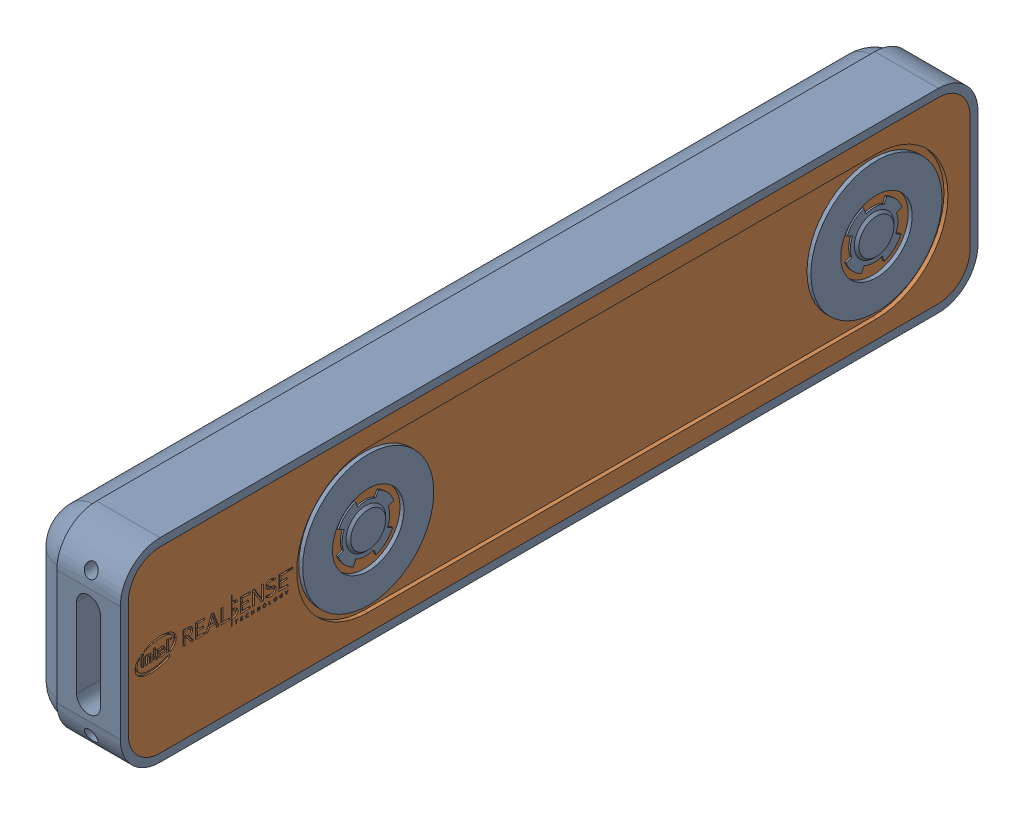
SolidWorks assembly Intel RealSense T265.step, configuration Default. Lengths in mm.
Overall size (12.5 24.5 108).
2 component instances, 2 part files, 0 mates.
Components (placement in the parent):
- body.step-1: body.step [Default] at (-0.0259 -0.3151 0.4547) x (1 0 0) z (0 1 0) size (12.5 108 24.5)
- cover.step-1: cover.step [Default] at (-0.0259 -0.3151 0.4547) x (1 0 0) z (0 1 0) size (1 106 22.5)
